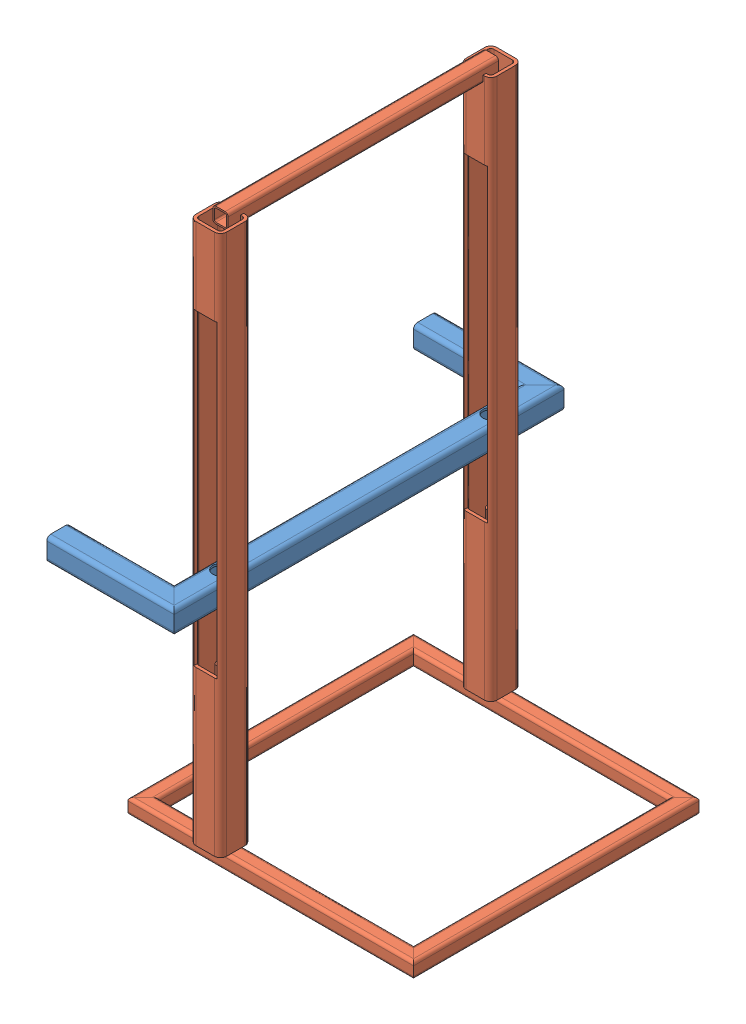
SolidWorks assembly assembly, configuration Default. Lengths in mm.
Overall size (409.9 730 505).
2 component instances, 2 part files, 3 mates.
Components (placement in the parent):
- manual arm-1: manual arm [Default<As Machined>] at (62.5733 43.1082 425.8926) size (165 30.03 505)
- manual base-1: manual base [Default<As Machined>] at (137.47 -257.1408 211.7321) size (370 730 390)
Mates (geometry in assembly coordinates):
- Concentric10: concentric anti-aligned: cylinder of manual arm-1 through (62.5733 13.1082 386.7919) axis (0 1 0) radius 10; cylinder of manual base-1 through (62.5733 367.8592 386.7919) axis (0 -1 0) radius 5
- Concentric11: concentric anti-aligned: cylinder of manual arm-1 through (62.5733 13.1082 36.7919) axis (0 1 0) radius 10; cylinder of manual base-1 through (62.5733 367.8592 36.7919) axis (0 -1 0) radius 5
- Parallel1: parallel anti-aligned: plane of manual arm-1 through (72.3733 28.1082 -28.2081) normal (0 -1 0); plane of manual base-1 through (-43.53 -247.1408 36.7321) normal (0 1 0)
